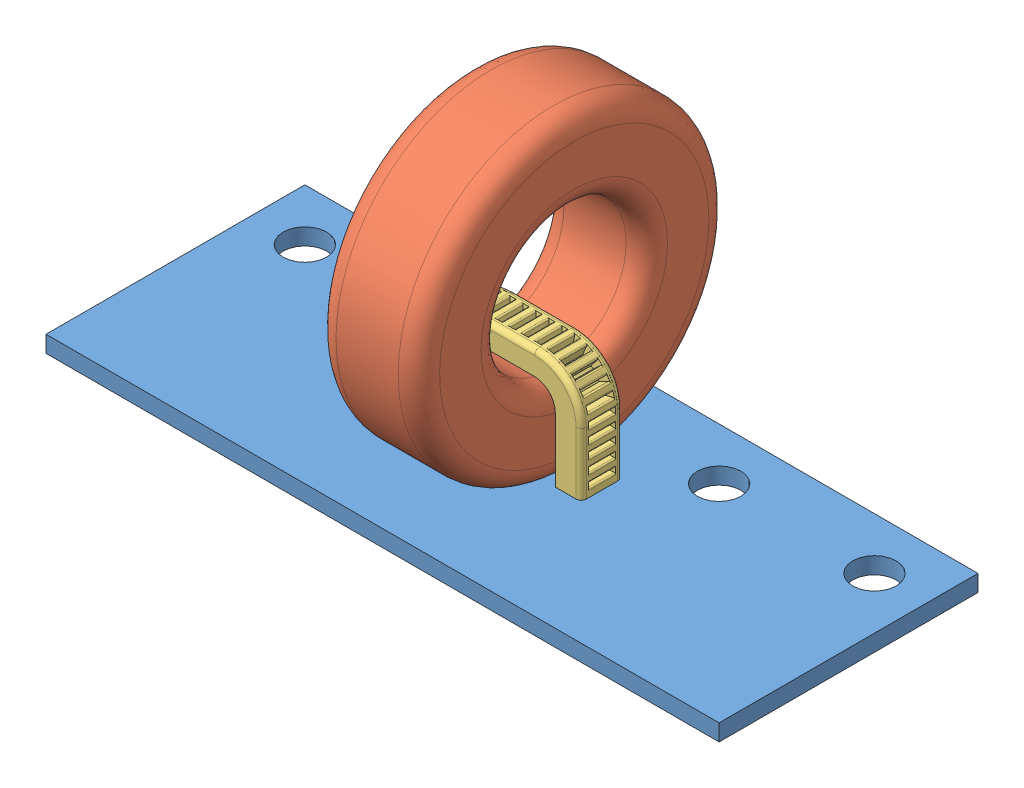
SolidWorks assembly silta_piirilevy_assy, configuration Default. Lengths in mm.
Overall size (65 42.04 42.04).
3 component instances, 3 part files, 4 mates.
Components (placement in the parent):
- silta_piirilevy-1: silta_piirilevy [Default] at (-30.5843 -0.828 16.7014) size (65 1.6 25)
- silta_toroidi-1: silta_toroidi [Default] at (-3.2092 24.8601 -8.8688) x (0 -0.605875 0.79556) z (-1 0 0) size (30 30 10)
- silta_nippuside-1: silta_nippuside [Default] at (-4.4592 0.772 2.8902) size (15 10.5 4)
Mates (geometry in assembly coordinates):
- Tangent1: tangent anti-aligned: plane of silta_piirilevy-1 through (-30.5843 0.772 -8.2986) normal (0 1 0); cylinder of silta_toroidi-1 through (-3.2092 15.772 3.0646) axis (-1 0 0) radius 15
- Angle4: planar angle = 0 rad anti-aligned: cylinder of silta_toroidi-1 through (-3.2092 15.772 3.0646) axis (-1 0 0) radius 15; line of silta_piirilevy-1 through (-30.5843 0.772 16.7014) axis (1 0 0)
- Coincident3: coincident anti-aligned: plane of silta_piirilevy-1 through (-30.5843 0.772 -8.2986) normal (0 1 0); plane of silta_nippuside-1 through (8.7908 0.772 1.3902) normal (0 -1 0)
- Coincident4: coincident anti-aligned: plane of silta_toroidi-1 through (6.7908 23.6483 -7.2776) normal (1 0 0); plane of silta_nippuside-1 through (6.7908 6.772 4.8902) normal (-1 0 0)
